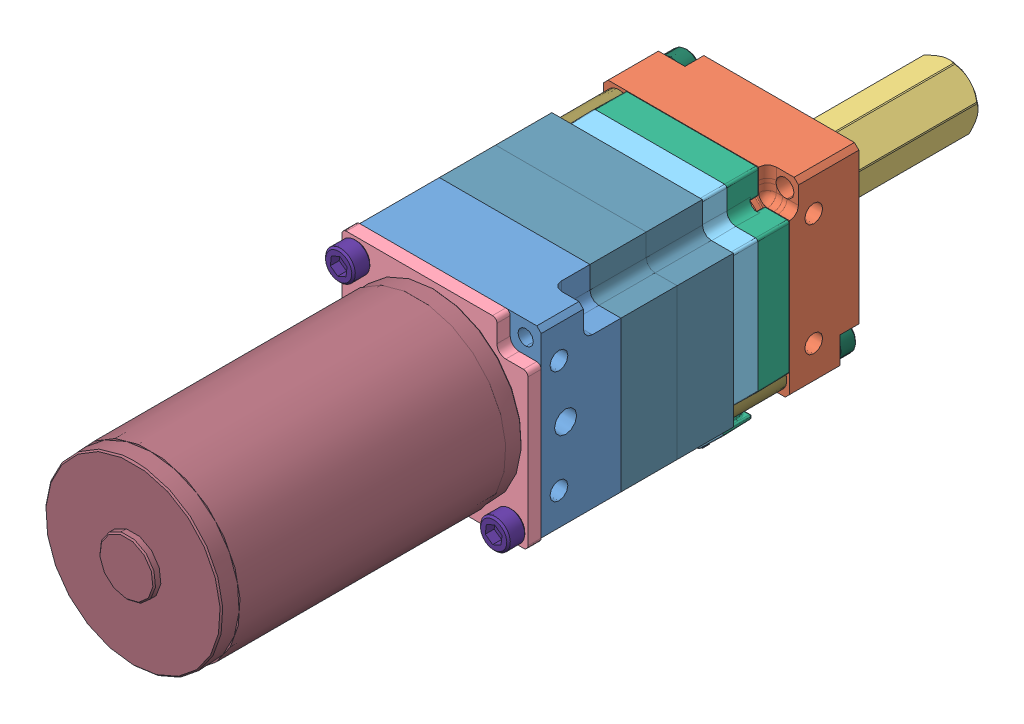
SolidWorks assembly VersaPlanetary_v1_Two_Stage_100_1_with_BAG, configuration Default. Lengths in mm.
Overall size (49.3 61.33 185.98).
51 component instances, 32 part files, 14 mates.
Components (placement in the parent):
- 217-2625-001 Rev1-1: 217-2625-001 Rev1 [Default] at origin size (42 42 18)
- 217-2625-002 Rev1-1: 217-2625-002 Rev1 [Default] at (0 0 -42.1) size (42 42 17.13)
- 217-2625-003 Rev1_1-1: 217-2625-003 Rev1_1 [Default] at (0 0 -56.0478) x (0.966651 -0.256095 0) z (0 0 -1) size (17 17 64.12)
- 217-2625-009 Rev1-1: 217-2625-009 Rev1 [Default] at (0 0 -3.48) x (-0.609619 0.792694 0) z (0 0 -1) size (18 18 13)
- 217-2625-100_1-1: 217-2625-100_1 [Default] at (0 0 -18.8454) x (0.784104 -0.62063 0) z (0 0 1) size (39.26 38.9 12.7)
  - 217-2625-008 Rev1_1-1: 217-2625-008 Rev1_1 [Default] at origin size (34.7 34.7 4.7)
  - 217-2625-010 Rev1_1-1: 217-2625-010 Rev1_1 [Default] at (0 10.193 3.65) x (0.999813 0.019336 0) z (0 0 1) size (4 4 12)
  - 217-2625-010 Rev1_1-2: 217-2625-010 Rev1_1 [Default] at (8.691 -5.3258 3.65) size (4 4 12)
  - 217-2625-010 Rev1_1-3: 217-2625-010 Rev1_1 [Default] at (-8.691 -5.3258 3.65) size (4 4 12)
  - 217-2625-005 Rev1_Planet_Revolving_Follower01_1-1: 217-2625-005 Rev1_Planet_Revolving_Follower01_1 [Default] at (8.691 -5.3258 6.35) x (0.932816 0.360354 0) z (0 0 1) size (16.91 16.92 8)
  - 217-2625-005 Rev1_Planet_Revolving_Follower01_1-2: 217-2625-005 Rev1_Planet_Revolving_Follower01_1 [Default] at (-8.691 -5.3258 6.35) x (-0.932788 -0.360426 0) z (0 0 1) size (16.91 16.92 8)
  - 217-2625-005 Rev1_Planet_Revolving_Follower01_1-3: 217-2625-005 Rev1_Planet_Revolving_Follower01_1 [Default] at (0 10.193 6.35) x (0.893583 0.448898 0) z (0 0 1) size (16.91 16.92 8)
- 217-2625-007 Rev1_Sun_Driver01-1: 217-2625-007 Rev1_Sun_Driver01 [Default] at (0 0 -11.5575) x (0.564419 -0.825488 0) z (0 0 1) size (14.49 14.49 12.72)
- 217-2742-1: 217-2742 [Default] at (0 0 -63.8002) x (0 0 1) z (-0.997393 0.072165 0) size (7 28 28)
- 217-2741-1: 217-2741 [Default] at (0 0 -7) x (0 0 1) z (-0.951311 0.308231 0) size (5 26 26)
- SSS1032-0125ZB_94105A824-1: SSS1032-0125ZB_94105A824 [Default] at (5.4759 4.2112 1.995) x (-0.605001 0.78669 -0.122849) z (0.792694 0.609619 0) size (4.83 4.84 3.3)
- TRUARC-5103-68_97414A675_grv-1: TRUARC-5103-68_97414A675_grv [Default] at (1.1965 0.0349 -1.3834) x (0 0 -1) z (-0.029125 0.999576 0) size (1.07 15.49 20.19)
- 217-3351-1: 217-3351 [Default] at (0 0 10.675) x (0 -1 0) z (0 0 -1) size (40.4 40.4 81.5)
- 217-2816-001 Rev1_1-1: 217-2816-001 Rev1_1 [Default] at (0 0 -29.55) x (1 0 0) z (0 0 -1) size (42 42 14.5)
- SSA_SSA0832-1750ZC-1: SSA_SSA0832-1750ZC [Default] at (17.5 -17.5 -59.961) x (0.465531 0.885032 0) z (-0.885032 0.465531 0) size (6.73 48.51 6.73)
- SSA_SSA0832-1750ZC-2: SSA_SSA0832-1750ZC [Default] at (-17.5 17.5 -59.961) x (0.228097 -0.973638 0) z (0.973638 0.228097 0) size (6.73 48.51 6.73)
- 217-2625-011 Rev1_1-1: 217-2625-011 Rev1_1 [Default] at (0 0 1.37) x (-0.792694 -0.609619 0) z (-0.609619 0.792694 0) size (8.01 7.5 7.94)
- SSA_SSA0832-0500ZC-1: SSA_SSA0832-0500ZC [Default] at (-17.5 17.5 10.675) x (0.592766 0.805375 0) z (0.805375 -0.592766 0) size (6.73 16.76 6.73)
- SSA_SSA0832-0500ZC-2: SSA_SSA0832-0500ZC [Default] at (17.5 -17.5 10.675) x (-0.592766 -0.805375 0) z (-0.805375 0.592766 0) size (6.73 16.76 6.73)
- SSHCM004_SSHCM004070010C-1: SSHCM004_SSHCM004070010C [Default] at (0 -12.5 7.5) x (-0.451598 -0.892221 0) z (0.892221 -0.451598 0) size (7 14 7)
- SSHCM004_SSHCM004070010C-2: SSHCM004_SSHCM004070010C [Default] at (0 12.5 7.5) x (-0.447517 -0.894275 0) z (0.894275 -0.447517 0) size (7 14 7)
- 217-2816-001 Rev1_1-2: 217-2816-001 Rev1_1 [Default] at (0 0 -16.85) x (1 0 0) z (0 0 -1) size (42 42 14.5)
- 217-2818 Rev1-1: 217-2818 Rev1 [Default] at (0 0 -31.5454) size (49.07 49.07 17.4)
  - 217-2725-001 Rev1_24t Sun-1: 217-2725-001 Rev1_24t Sun [Default] at (0 0 8.7) size (14.45 14.45 12.7)
  - 217-2725-002 Rev1_24t Planet-1: 217-2725-002 Rev1_24t Planet [Default] at (-12.089 0 6.35) x (-0.130526 0.991445 0) z (0 0 -1) size (13.17 13.15 8)
  - 217-2724-002 Rev1-1: 217-2724-002 Rev1 [Default] x (0.707107 -0.707107 0) z (0 0 -1) size (34.7 34.7 4.7)
  - 217-2625-010 Rev1_1-1: 217-2625-010 Rev1_1 [Default] at (-12.089 0 3.65) x (0.971612 -0.236582 0) z (0 0 1) size (4 4 12)
  - 217-2725-002 Rev1_24t Planet-2: 217-2725-002 Rev1_24t Planet [Default] at (0 -12.089 6.35) x (-0.991445 -0.130526 0) z (0 0 -1) size (13.17 13.15 8)
  - 217-2725-002 Rev1_24t Planet-3: 217-2725-002 Rev1_24t Planet [Default] at (12.089 0 6.35) x (0.130526 -0.991445 0) z (0 0 -1) size (13.17 13.15 8)
  - 217-2725-002 Rev1_24t Planet-4: 217-2725-002 Rev1_24t Planet [Default] at (0 12.089 6.35) x (0.991445 0.130526 0) z (0 0 -1) size (13.17 13.15 8)
  - 217-2625-010 Rev1_1-2: 217-2625-010 Rev1_1 [Default] at (0 -12.089 3.65) x (0.236582 0.971612 0) z (0 0 1) size (4 4 12)
  - 217-2625-010 Rev1_1-3: 217-2625-010 Rev1_1 [Default] at (12.089 0 3.65) x (-0.971612 0.236582 0) z (0 0 1) size (4 4 12)
  - 217-2625-010 Rev1_1-4: 217-2625-010 Rev1_1 [Default] at (0 12.089 3.65) x (-0.236582 -0.971612 0) z (0 0 1) size (4 4 12)
- 217-2822-003 Rev4_1-1: 217-2822-003 Rev4_1 [Default] at (0 0 9) x (0 -1 0) z (0 0 1) size (42 42 4.8)
- VersaPlanetary_Integrated_Encoder_217-5046-1: VersaPlanetary_Integrated_Encoder_217-5046 [Default] at (0 0 -41.4) x (0 1 0) z (0 0 1) size (58.21 43.13 22.65)
  - 217-4783-001 Rev3-1: 217-4783-001 Rev3 [Default] at (0 0 2.75) size (53.55 42 11.11)
  - 217-4783-002 Rev7_Sealed Config-1: 217-4783-002 Rev7_Sealed Config [Default] at (0 0 -7.2) x (0 1 0) z (0 0 1) size (42 51.56 9.32)
  - 217-4783-005 Rev7_40t_spur_REF_14deg-1: 217-4783-005 Rev7_40t_spur_REF_14deg [Default] at (0 0 5.95) x (0.660339 0.750968 0) z (0 0 1) size (21.16 21.1 17.1)
  - 217-4783-004 Rev2_40t_spur_REF_14deg-1: 217-4783-004 Rev2_40t_spur_REF_14deg [Default] at (-20.05 0 5.2) x (-0.718289 0.695745 0) z (0 0 1) size (21.07 21.07 4.88)
  - 217-4783-008 Rev2-1: 217-4783-008 Rev2 [Default] at (-20.05 0 2.2) x (0.307149 -0.951661 0) z (0.951661 0.307149 0) size (5 4 5)
  - PCBA Rev3-1: PCBA Rev3 [Default] at (-20.05 0 -2.1252) x (0 1 0) z (-1 0 0) size (15.93 10.15 24.58)
  - 217-2788-001 Rev3_57155K375-1: 217-2788-001 Rev3_57155K375 [Default] at (-20.05 0 3.8125) x (-0.99574 0.092202 0) z (0 0 1) size (9.53 9.53 3.17)
  - 217-4783-006 Rev3-1: 217-4783-006 Rev3 [Default] at (17.5 17.5 -0.85) x (-0.867641 0.497191 0) z (0 0 1) size (5.9 5.9 12.7)
  - 217-4783-006 Rev3-2: 217-4783-006 Rev3 [Default] at (-17.5 -17.5 -0.85) x (0.825154 -0.564908 0) z (0 0 1) size (5.9 5.9 12.7)
  - 217-4783-007 Rev1-1: 217-4783-007 Rev1 [Default] at (-16.45 0 -5.2) x (0 1 0) z (0 0 1) size (6 10.71 3.56)
  - 217-4783-003 Rev4-1: 217-4783-003 Rev4 [Default] at (-20.05 0 -1.02) x (0 1 0) z (0 0 1) size (23.4 21.71 4.21)
Mates (geometry in assembly coordinates):
- Coincident1: coincident aligned: circle of 217-2625-002 Rev1-1; plane of 217-2742-1 through (0.9201 12.7168 -56.8002) normal (0 0 1)
- Concentric1: concentric aligned: circle of 217-2625-002 Rev1-1; circle of 217-2742-1
- Concentric2: concentric anti-aligned: circle of 217-2625-003 Rev1_1-1; circle of 217-2742-1
- Coincident2: coincident anti-aligned: plane of 217-2625-003 Rev1_1-1 through (0 0 -63.8002) normal (0 0 1); plane of 217-2742-1 through (0.6314 8.7272 -63.8002) normal (0 0 -1)
- Concentric3: concentric aligned: circle of 217-2625-002 Rev1-1; circle of SSA_SSA0832-1750ZC-2
- Concentric4: concentric anti-aligned: circle of 217-2625-002 Rev1-1; circle of SSA_SSA0832-1750ZC-1
- Coincident3: coincident anti-aligned: plane of 217-2625-002 Rev1-1 through (-14 21 -59.961) normal (0 0 -1); plane of SSA_SSA0832-1750ZC-2 through (-17.5 17.5 -59.961) normal (0 0 1)
- Coincident4: coincident anti-aligned: plane of 217-2625-002 Rev1-1 through (14 -21 -59.961) normal (0 0 -1); plane of SSA_SSA0832-1750ZC-1 through (17.5 -17.5 -59.961) normal (0 0 1)
- Concentric5: concentric aligned: circle of 217-2816-001 Rev1_1-1; circle of VersaPlanetary_Integrated_Encoder_217-5046-1/217-4783-006 Rev3-1
- Concentric6: concentric aligned: circle of 217-2816-001 Rev1_1-1; circle of VersaPlanetary_Integrated_Encoder_217-5046-1/217-4783-006 Rev3-2
- Coincident5: coincident anti-aligned: plane of 217-2816-001 Rev1_1-1 through (21 -21 -35.9) normal (0 0 -1); plane of VersaPlanetary_Integrated_Encoder_217-5046-1/217-4783-001 Rev3-1 through (0 0 -35.9) normal (0 0 1)
- Concentric7: concentric anti-aligned: circle of SSA_SSA0832-1750ZC-2; circle of VersaPlanetary_Integrated_Encoder_217-5046-1/217-4783-006 Rev3-1
- Concentric8: concentric anti-aligned: circle of SSA_SSA0832-1750ZC-1; circle of VersaPlanetary_Integrated_Encoder_217-5046-1/217-4783-006 Rev3-2
- Coincident6: coincident anti-aligned: plane of 217-2625-002 Rev1-1 through (0 0 -48.6) normal (0 0 1); plane of VersaPlanetary_Integrated_Encoder_217-5046-1/217-4783-002 Rev7_Sealed Config-1 through (0 0 -48.6) normal (0 0 -1)
